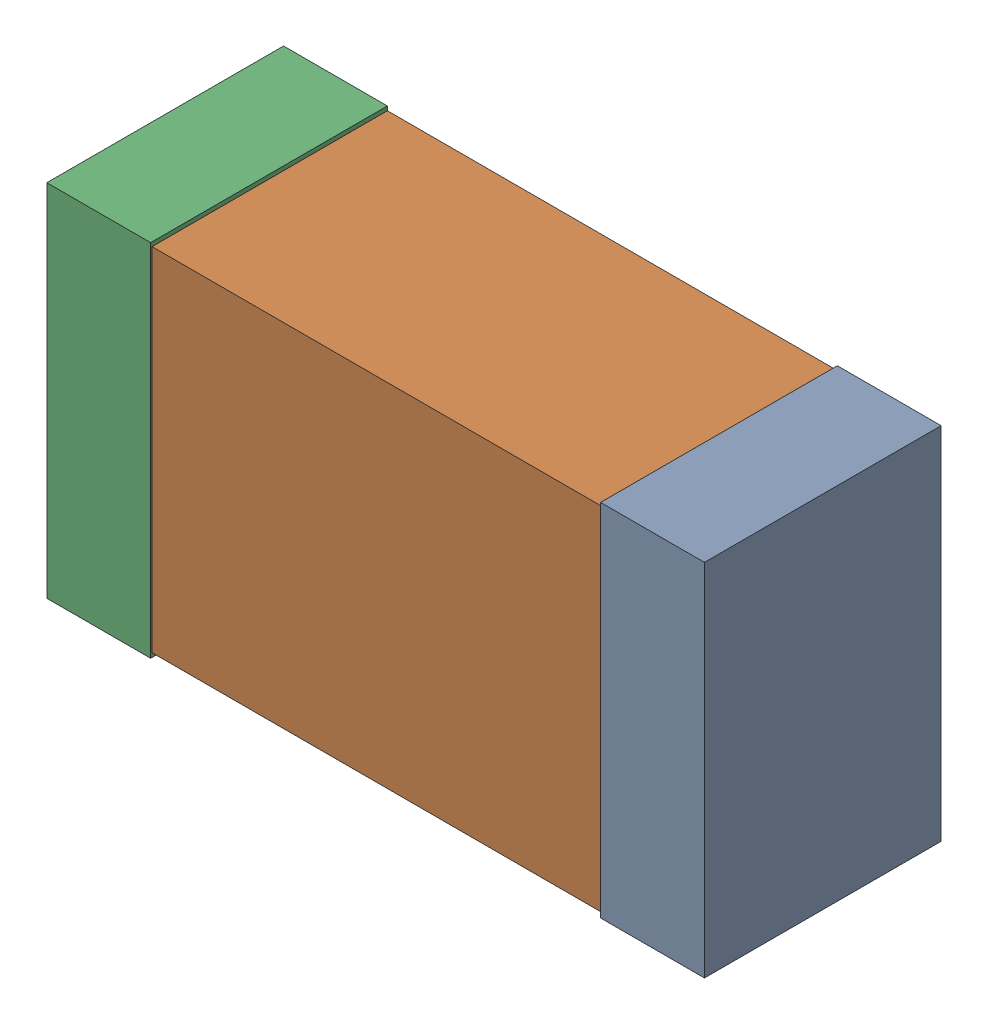
SolidWorks assembly C3, configuration Default. Lengths in mm.
Overall size (2.38 1.3 0.85).
6 component instances, 2 part files, 0 mates.
Components (placement in the parent):
- 384311232-1: 384311232 [Default] at (152.4094 88.5698 0) size (0.38 1.3 0.85)
  - Extruded_8-1: Extruded_8 [Default] at origin size (0.38 1.3 0.85)
- 384311360-1: 384311360 [Default] at (151.4094 88.5698 0) size (2.2 1.27 0.85)
  - Extruded_9-1: Extruded_9 [Default] at origin size (2.2 1.27 0.85)
- 384311232-2: 384311232 [Default] at (150.4094 88.5698 0) size (0.38 1.3 0.85)
  - Extruded_8-1: Extruded_8 [Default] at origin size (0.38 1.3 0.85)
